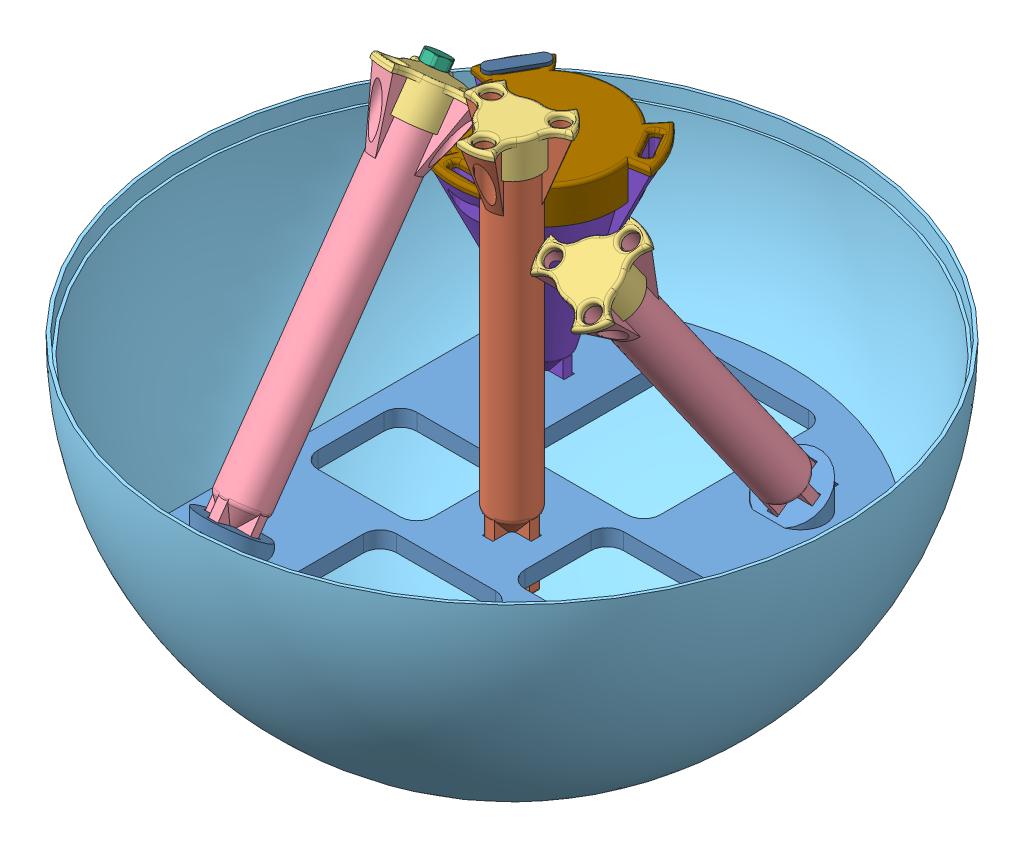
SolidWorks assembly cross_phantom, configuration Default. Lengths in mm.
Overall size (229.87 157.85 229.87).
14 component instances, 10 part files, 34 mates.
Components (placement in the parent):
- bottom_plate_cross-1: bottom_plate_cross [Default] at origin size (110 16.14 167.4)
- cylinder_cross_v2-1: cylinder_cross_v2 [Default] at (0 60.0092 0) x (-1 0 0) z (0 0 1) size (26.98 121 26.12)
- lid_cross_v2-1: lid_cross_v2 [Default] at (0 111.0092 0) x (0 1 0) z (0.173648 0 -0.984808) size (11.32 27.15 28.3)
- lid_cross_v2-2: lid_cross_v2 [Default] at (37.5 96.909 13.3544) x (0 0.819152 0.573576) z (-0.642788 -0.439385 0.627507) size (11.32 27.15 28.3)
- cylinder_slanted_v2-1: cylinder_slanted_v2 [Default] at (37.5 55.1323 -15.898) x (0 0.573576 -0.819152) z (-1 0 0) size (26.98 123 26.12)
- cylinder_slanted_v2-2: cylinder_slanted_v2 [Default] at (-37.5 55.1323 15.898) x (0 0.573576 0.819152) z (1 0 0) size (26.98 123 26.12)
- lid_cross_v2-3: lid_cross_v2 [Default] at (-37.5 96.909 -13.3544) x (0 0.819152 -0.573576) z (-0.984808 -0.0996 -0.142244) size (11.32 27.15 28.3)
- shell-1: shell [Default] at (0.075 54.4851 0.4549) x (-0.986677 0 0.162689) z (0 -1 0) size (200 200 100)
- pin_v2_5mm-1: pin_v2_5mm [Default] at (-44.2493 94.3434 -21.3771) x (-0.999603 0.016152 0.023067) z (0 -0.819152 0.573576) size (7.77 7 16.5)
- pin_v2_4mm-1: pin_v2_4mm [Default] at (-40.4246 -2.9499 51.5025) x (0 0.974896 0.222661) z (1 0 0) size (5.46 5 11.5)
- pin_v2_4mm-2: pin_v2_4mm [Default] at (-4.1687 -3.9908 -2.8557) x (0.796124 0.605134 0) z (0 0 1) size (5.46 5 11.5)
- cone_cross-1: cone_cross [Default] at (-37.5 -10 -47.5) x (0 0 1) z (-1 0 0) size (47.86 76 53.54)
- lid_cone-1: lid_cone [Default] at (-37.5 66 -47.5) x (0 1 0) z (0.642788 0 0.766044) size (11.09 51.87 54)
- rectangular_pin-1: rectangular_pin [Default] at (-57.8516 68 -59.25) x (-0.5 0 0.866025) z (0.866025 0 0.5) size (16 16 4)
Mates (geometry in assembly coordinates):
- Concentric10: concentric: circle of lid_cross_v2-1; circle of cylinder_cross_v2-1
- LimitDistance1: limit distance = 0 mm: plane of lid_cross_v2-1 through (3.6 110.0092 6.2354) normal (0 -1 0); plane of cylinder_cross_v2-1 through (0 110.0092 0) normal (0 1 0)
- Concentric11: concentric: circle of bottom_plate_cross-1; cylinder of cylinder_cross_v2-1 through (0 10.0092 0) axis (0 1 0) radius 7
- Parallel1: parallel: plane of bottom_plate_cross-1 through (7.4 -5 1.575) normal (-1 0 0); plane of cylinder_cross_v2-1 through (6.875 -9.9908 0) normal (1 0 0)
- Concentric13: concentric: circle of bottom_plate_cross-1; cylinder of cylinder_slanted_v2-1 through (37.5 14.1747 -44.5769) axis (0 0.819152 0.573576) radius 7
- Parallel2: parallel: plane of bottom_plate_cross-1 through (35.925 -39.3261 -27.5365) normal (1 0 0); plane of cylinder_slanted_v2-1 through (38.95 -3.8467 -57.1955) normal (1 0 0)
- Concentric15: concentric: circle of lid_cross_v2-2; circle of cylinder_slanted_v2-1
- LimitDistance3: limit distance = 0 mm: plane of lid_cross_v2-2 through (31.2646 94.025 15.7297) normal (0 -0.819152 -0.573576); plane of cylinder_slanted_v2-1 through (37.5 96.0899 12.7808) normal (0 0.819152 0.573576)
- Coincident17: coincident: plane of lid_cross_v2-2 through (37.5 96.909 13.3544) normal (0.5 0.496732 -0.709406); plane of cylinder_slanted_v2-1 through (37.5 55.1323 -15.898) normal (0.5 0.496732 -0.709406)
- Coincident18: coincident: plane of cylinder_cross_v2-1 through (0 60.0092 0) normal (0.866025 0 -0.5); plane of lid_cross_v2-1 through (0 111.0092 0) normal (0.866025 0 -0.5)
- LimitDistance5: limit distance = -1 mm: plane of bottom_plate_cross-1 through (37.5 10 -47.5) normal (0 0.819152 0.573576); point of cylinder_slanted_v2-1
- LimitDistance6: limit distance = -1 mm: plane of bottom_plate_cross-1 through (0 5 0) normal (0 1 0); unknown of cylinder_cross_v2-1
- Concentric16: concentric: circle of bottom_plate_cross-1; circle of cylinder_slanted_v2-2
- Parallel3: parallel: plane of bottom_plate_cross-1 through (0 -12.8152 65.3981) normal (0 -0.573576 -0.819152); plane of cylinder_slanted_v2-2 through (-37.5 -4.6784 56.0078) normal (0 -0.573576 -0.819152)
- LimitDistance7: limit distance = -1 mm: unknown of cylinder_slanted_v2-2; plane of bottom_plate_cross-1 through (-37.5 10 47.5) normal (0 0.819152 -0.573576)
- Concentric17: concentric: circle of cylinder_slanted_v2-2; circle of lid_cross_v2-3
- Parallel4: parallel: plane of cylinder_slanted_v2-2 through (-37.5 55.1323 15.898) normal (1 0 0); plane of lid_cross_v2-3 through (-37.5 96.909 -13.3544) normal (1 0 0)
- LimitDistance8: limit distance = 0 mm: plane of lid_cross_v2-3 through (-37.5 96.909 -13.3544) normal (0 -0.819152 0.573576); plane of cylinder_slanted_v2-2 through (-37.5 96.909 -13.3544) normal (0 0.819152 -0.573576)
- Concentric19: concentric: cylinder of cylinder_cross_v2-1 through (0 10.0092 0) axis (0 1 0) radius 7; circle of shell-1
- Tangent8: tangent: torus of bottom_plate_cross-1; sphere of shell-1
- Concentric20: concentric: circle of lid_cross_v2-3; circle of pin_v2_5mm-1
- Concentric21: concentric: circle of cylinder_slanted_v2-2; circle of pin_v2_4mm-1
- LimitDistance9: limit distance = 0 mm: plane of pin_v2_5mm-1 through (-44.2493 93.1146 -20.5168) normal (0 -0.819152 0.573576); plane of lid_cross_v2-3 through (-37.5 97.7282 -13.9279) normal (0 0.819152 -0.573576)
- Concentric22: concentric: circle of cylinder_cross_v2-1; circle of pin_v2_4mm-2
- Concentric23: concentric: circle of bottom_plate_cross-1; circle of cone_cross-1
- Parallel7: parallel: plane of bottom_plate_cross-1 through (0 -5 -45.925) normal (0 0 -1); plane of cone_cross-1 through (-37.5 10 -46.125) normal (0 0 1)
- LimitDistance10: limit distance = 10 mm: plane of cone_cross-1 through (-37.5 -10 -47.5) normal (0 -1 0); plane of bottom_plate_cross-1 through (0 0 0) normal (0 -1 0)
- Concentric24: concentric: circle of cone_cross-1; circle of lid_cone-1
- Parallel8: parallel: plane of cone_cross-1 through (-56.6162 -10 -64.3897) normal (-0.5 0 0.866025); plane of lid_cone-1 through (-54.0526 75 -62.8301) normal (-0.5 0 0.866025)
- LimitDistance11: limit distance = 0 mm: plane of lid_cone-1 through (-37.5 66 -47.5) normal (0 -1 0); plane of cone_cross-1 through (-37.5 66 -47.5) normal (0 1 0)
- Parallel9: parallel: plane of lid_cone-1 through (-56.5526 75 -58.5) normal (-0.866025 0 -0.5); plane of rectangular_pin-1 through (-59.0983 52 -54.3406) normal (0.866025 0 0.5)
- Parallel10: parallel: plane of lid_cone-1 through (-61.6506 75 -55.6699) normal (0.5 0 -0.866025); plane of rectangular_pin-1 through (-59.0983 52 -54.3406) normal (-0.5 0 0.866025)
- Concentric25: concentric: circle of lid_cone-1; circle of rectangular_pin-1
- LimitDistance13: limit distance = 0 mm: plane of lid_cone-1 through (-37.5 67 -47.5) normal (0 1 0); plane of rectangular_pin-1 through (-60.8516 67 -54.0538) normal (0 -1 0)
